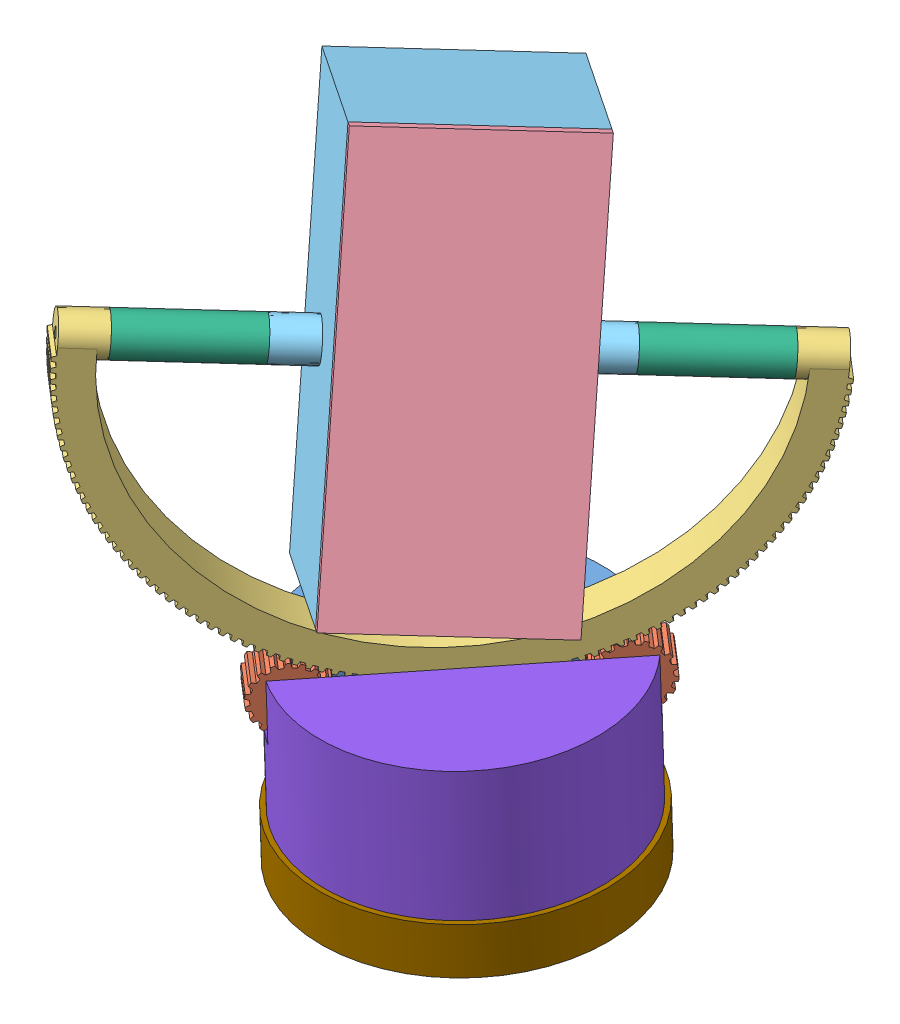
SolidWorks assembly SS test rig V2, configuration Default. Lengths in mm.
Overall size (224.22 357.69 252.07).
15 component instances, 9 part files, 27 mates.
Components (placement in the parent):
- Base 1-1: Base 1 [Default] at (-64.2352 -29.6328 -6.0392) x (-0.759755 0.022466 -0.649821) z (0.65021 0.026251 -0.759301) size (85 70 150)
- gear-1: gear [Default] at (-114.5317 29.3319 39.416) x (0.650171 0.037176 -0.758878) z (0.759755 -0.022466 0.649821) size (33.83 34 24)
- gear-2: gear [Default] at (-30.0045 32.7444 -59.2931) x (0.619014 -0.280854 -0.733445) z (0.759755 -0.022466 0.649821) size (33.83 34 24)
- gear-3: gear [Default] at (-57.073 17.5966 2.6087) x (-0.643632 0.115816 0.756522) z (-0.759755 0.022466 -0.649821) size (33.83 34 24)
- Test rig-1: Test rig [Default] at (-56.6376 185.0142 7.8876) x (0.645843 -0.089555 -0.7582) z (0.075228 0.995728 -0.053531) size (303.88 20 162)
- Sat Case Lid-1: Sat Case Lid [Default] at (-12.3634 290.775 -32.8368) x (0.175693 -0.949009 0.261751) z (0.645843 -0.089555 -0.7582) size (200 10 100)
- Sat Case-1: Sat Case [Default] at (-86.6613 260.5489 -92.5545) x (-0.645843 0.089555 0.7582) z (0.742979 0.302261 0.597177) size (140 200 95)
- Rod-1: Rod [Default] at (32.6413 171.8055 -112.3406) x (-0.329065 -0.928769 -0.170599) z (-0.688914 0.359677 -0.629309) size (20 100 20)
- Rod-2: Rod [Default] at (-96.5273 189.7166 39.2994) x (-0.687863 0.362634 -0.628762) z (0.331258 0.927619 0.172603) size (20 100 20)
- wheels-1: wheels [Default] at (-105.6418 -28.4084 -41.4544) x (-0.759755 0.022466 -0.649821) z (0.630877 0.267363 -0.728362) size (14 40 40)
- Base 2-1: Base 2 [Default] at (-64.2352 -29.6328 -6.0392) x (0.759755 -0.022466 0.649821) z (-0.65021 -0.026251 0.759301) size (75 70 150)
- wheels-2: wheels [Default] at (-99.6716 -31.0635 35.3428) x (-0.65021 -0.026251 0.759301) z (-0.737165 0.263691 -0.622137) size (14 40 40)
- wheels-3: wheels [Default] at (-22.8285 -30.8572 29.3761) x (0.759755 -0.022466 0.649821) z (-0.630877 0.216423 0.745087) size (14 40 40)
- wheels-4: wheels [Default] at (-28.7987 -28.2022 -47.4211) x (0.65021 0.026251 -0.759301) z (0.737165 0.220096 0.638863) size (14 40 40)
- Track-1: Track [Default] at (-64.2352 -29.6328 -6.0392) x (0.155199 -0.034133 0.987293) z (0.987883 0.005362 -0.155106) size (155 25 155)
Mates (geometry in assembly coordinates):
- Concentric2: concentric anti-aligned: cylinder of Base 1-1 through (-116.0513 29.3768 38.1164) axis (0.759755 -0.022466 0.649821) radius 1; cylinder of gear-1 through (-97.8171 28.8376 53.7121) axis (-0.759755 0.022466 -0.649821) radius 1
- Coincident1: coincident anti-aligned: plane of Base 1-1 through (-71.8327 185.4635 -5.1088) normal (0.759755 -0.022466 0.649821); plane of gear-1 through (-114.5317 29.3319 39.416) normal (-0.759755 0.022466 -0.649821)
- Concentric3: concentric anti-aligned: cylinder of Base 1-1 through (-31.524 32.7894 -60.5928) axis (0.759755 -0.022466 0.649821) radius 1; cylinder of gear-2 through (-13.2899 32.2502 -44.9971) axis (-0.759755 0.022466 -0.649821) radius 1
- Coincident2: coincident anti-aligned: plane of Base 1-1 through (-71.8327 185.4635 -5.1088) normal (0.759755 -0.022466 0.649821); plane of gear-2 through (-30.0045 32.7444 -59.2931) normal (-0.759755 0.022466 -0.649821)
- Concentric4: concentric anti-aligned: cylinder of Base 1-1 through (-73.7876 18.0908 -11.6874) axis (0.759755 -0.022466 0.649821) radius 1; cylinder of gear-3 through (-55.5535 17.5517 3.9084) axis (-0.759755 0.022466 -0.649821) radius 1
- Coincident3: coincident anti-aligned: plane of Base 1-1 through (-71.8327 185.4635 -5.1088) normal (0.759755 -0.022466 0.649821); plane of gear-3 through (-72.2681 18.0459 -10.3877) normal (-0.759755 0.022466 -0.649821)
- Concentric5: concentric anti-aligned: cylinder of Base 1-1 through (-71.8327 185.4635 -5.1088) axis (-0.759755 0.022466 -0.649821) radius 190; cylinder of Test rig-1 through (-71.8327 185.4635 -5.1088) axis (0.759755 -0.022466 0.649821) radius 135
- Coincident4: coincident anti-aligned: plane of Base 1-1 through (-71.8327 185.4635 -5.1088) normal (0.759755 -0.022466 0.649821); plane of Test rig-1 through (-71.8327 185.4635 -5.1088) normal (-0.759755 0.022466 -0.649821)
- GearMate1: gear = 100 : 1000 mm: line of gear-1 through (-95.0565 44.7516 47.9568) axis (-0.613392 0.306763 0.727768); circle of Test rig-1
- GearMate2: gear = 100 : 1000 mm: line of gear-3 through (-56.1483 34.5937 2.1152) axis (0.643632 -0.115816 -0.756522); circle of Test rig-1
- GearMate3: gear = 100 : 1000 mm: line of gear-2 through (-14.5801 49.3199 -45.9762) axis (-0.649739 -0.064247 0.757437); circle of Test rig-1
- Coincident5: coincident anti-aligned: plane of Sat Case-1 through (-19.0261 178.9699 -51.6846) normal (0.645843 -0.089555 -0.7582); plane of Rod-1 through (-19.0261 178.9699 -51.6846) normal (-0.645843 0.089555 0.7582)
- Coincident6: coincident anti-aligned: circle of Sat Case-1; cylinder of Rod-1 through (-19.0261 178.9699 -51.6846) axis (-0.645843 0.089555 0.7582) radius 2.5
- Concentric6: concentric anti-aligned: cylinder of Sat Case-1 through (-109.4442 191.5077 54.4633) axis (0.645843 -0.089555 -0.7582) radius 2.5; cylinder of Rod-2 through (-148.1948 196.881 99.9553) axis (-0.645843 0.089555 0.7582) radius 2.5
- Coincident7: coincident anti-aligned: plane of Sat Case-1 through (-109.4442 191.5077 54.4633) normal (-0.645843 0.089555 0.7582); plane of Rod-2 through (-109.4442 191.5077 54.4633) normal (0.645843 -0.089555 -0.7582)
- Concentric7: concentric anti-aligned: cylinder of Test rig-1 through (-148.1948 196.881 99.9553) axis (-0.645843 0.089555 0.7582) radius 2.5; cylinder of Rod-1 through (19.7244 173.5966 -97.1766) axis (0.645843 -0.089555 -0.7582) radius 2.5
- Coincident8: coincident anti-aligned: plane of Test rig-1 through (-148.1948 196.881 99.9553) normal (0.645843 -0.089555 -0.7582); plane of Rod-2 through (-148.1948 196.881 99.9553) normal (-0.645843 0.089555 0.7582)
- Coincident14: coincident anti-aligned: plane of Sat Case Lid-1 through (-16.0783 289.2637 -35.8227) normal (-0.742979 -0.302261 -0.597177); plane of Sat Case-1 through (-16.0783 289.2637 -35.8227) normal (0.742979 0.302261 0.597177)
- Coincident15: coincident aligned: plane of Sat Case Lid-1 through (-80.6626 298.2192 39.9972) normal (-0.645843 0.089555 0.7582); plane of Sat Case-1 through (-116.1069 79.7026 35.6156) normal (-0.645843 0.089555 0.7582)
- Coincident16: coincident aligned: plane of Sat Case Lid-1 through (-16.0783 289.2637 -35.8227) normal (-0.175693 0.949009 -0.261751); plane of Sat Case-1 through (-86.6613 260.5489 -92.5545) normal (-0.175693 0.949009 -0.261751)
- Concentric8: concentric aligned: cylinder of Base 1-1 through (-103.7424 -28.4646 -39.8299) axis (-0.759755 0.022466 -0.649821) radius 1; cylinder of wheels-1 through (-104.1223 -28.4534 -40.1548) axis (-0.759755 0.022466 -0.649821) radius 1
- Concentric10: concentric aligned: cylinder of Base 1-1 through (-102.1523 -21.701 53.9556) axis (-0.759755 0.022466 -0.649821) radius 2.5; cylinder of Base 2-1 through (-102.1523 -21.701 53.9556) axis (-0.759755 0.022466 -0.649821) radius 2.5
- Coincident19: coincident anti-aligned: plane of Base 1-1 through (-102.1523 -21.701 53.9556) normal (0.759755 -0.022466 0.649821); plane of Base 2-1 through (-102.1523 -21.701 53.9556) normal (-0.759755 0.022466 -0.649821)
- Coincident20: coincident aligned: plane of Base 1-1 through (-64.2352 -29.6328 -6.0392) normal (0 -0.999403 -0.034551); plane of Base 2-1 through (-64.2352 -29.6328 -6.0392) normal (0 -0.999403 -0.034551)
- Distance1: distance = 0.5 mm anti-aligned: plane of wheels-1 through (-114.7589 -28.1388 -49.2523) normal (-0.759755 0.022466 -0.649821); plane of Base 1-1 through (-115.1387 -28.1276 -49.5772) normal (0.759755 -0.022466 0.649821)
- Coincident23: coincident anti-aligned: plane of Base 1-1 through (-64.2352 -29.6328 -6.0392) normal (0 -0.999403 -0.034551); plane of Track-1 through (-64.2352 -29.6328 -6.0392) normal (0 0.999403 0.034551)
- Concentric11: concentric anti-aligned: circle of Base 1-1; circle of Track-1
